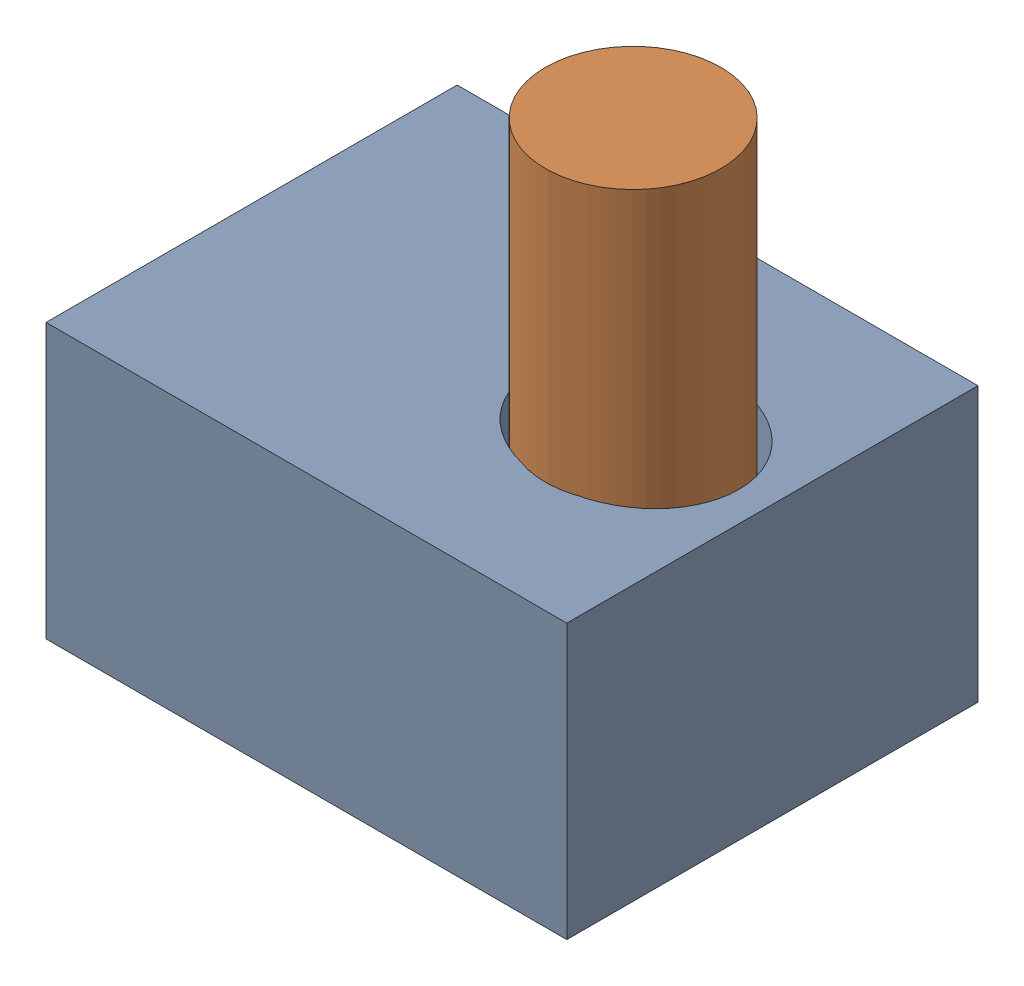
SolidWorks assembly mast model, configuration Default. Lengths in mm.
Overall size (190 199.12 150).
2 component instances, 2 part files, 0 mates.
Components (placement in the parent):
- mast model hull-1: mast model hull [Default] at (-54.5534 10.2691 163.7951) x (1 0 0) z (0 1 0) size (190 150 100)
- mast model mast-1: mast model mast [Default] at (175.4914 209.3906 51.5979) x (1 0 0) z (0 -1 0) size (64 64 170)
